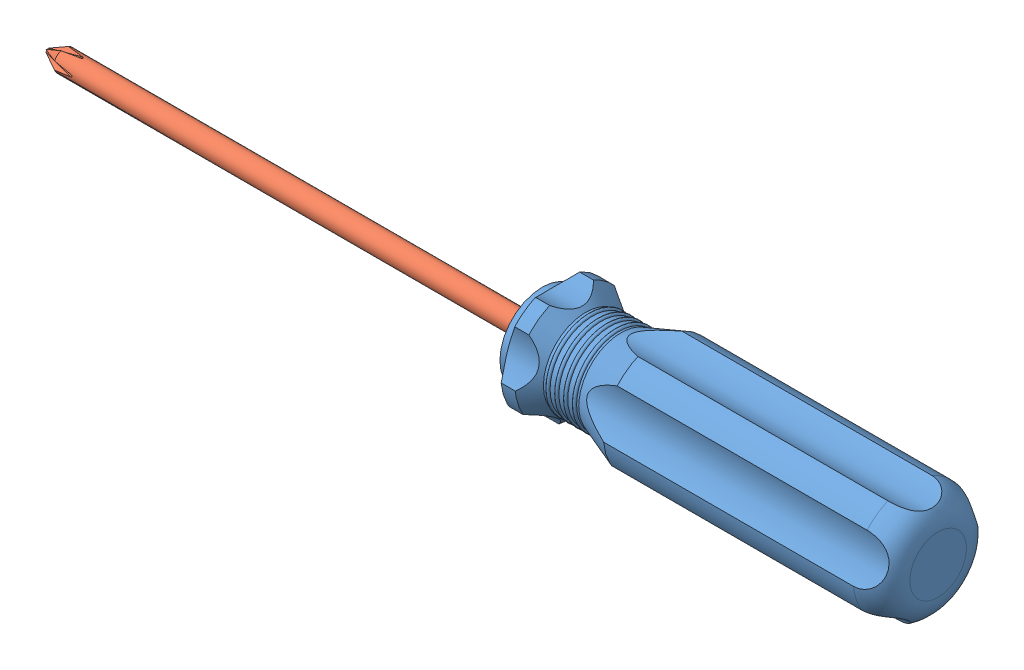
SolidWorks assembly Screw Driver, configuration Default. Lengths in mm.
Overall size (126 16.24 17.02).
2 component instances, 2 part files, 2 mates.
Components (placement in the parent):
- Handle-1: Handle [Default] at (10.6561 35.2182 45.1033) size (56 16.24 17.02)
- Head-1: Head [Default] at (-59.3439 35.2182 45.1033) x (1 0 0) z (0 0.028716 0.999588) size (100 4 4)
Mates (geometry in assembly coordinates):
- Concentric1: concentric: cylinder of Handle-1 through (40.6561 35.2182 45.1033) axis (-1 0 0) radius 1.5; cylinder of Head-1 through (-108.2387 35.2182 45.1033) axis (-1 0 0) radius 1.5
- Coincident1: coincident: plane of Handle-1 through (40.6561 35.2182 45.1033) normal (-1 0 0); plane of Head-1 through (40.6561 35.2182 45.1033) normal (1 0 0)
